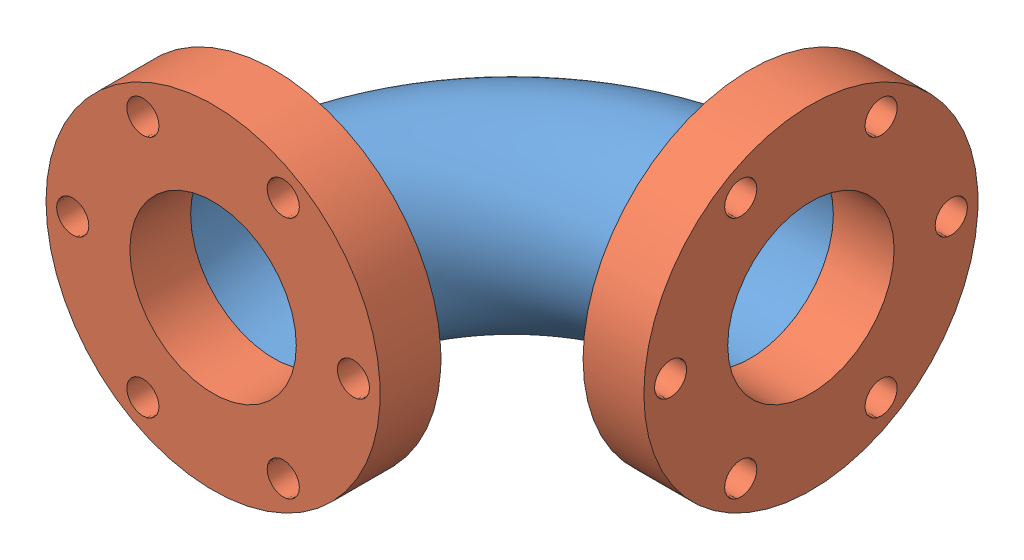
SolidWorks assembly 2.75in_elbow, configuration Default. Lengths in mm.
Overall size (97.41 69.85 97.41).
3 component instances, 2 part files, 3 mates.
Components (placement in the parent):
- 2.75in_elbow_tube-1: 2.75in_elbow_tube [Default] at (41.1147 -0.9291 41.2148) size (68.83 38.1 68.83)
- 2.75in_CF_flange-3: 2.75in_CF_flange [Default] at (-8.6693 -0.9291 53.9148) x (0 -1 0) z (1 0 0) size (69.85 12.7 69.85)
- 2.75in_CF_flange-4: 2.75in_CF_flange [Default] at (41.1147 -0.9291 -8.5692) x (0 1 0) z (0 0 -1) size (69.85 12.7 69.85)
Mates (geometry in assembly coordinates):
- Parallel2: parallel anti-aligned: line of 2.75in_CF_flange-4 through (41.1147 -0.9291 -8.5692) axis (0 0 1); line of assembly
- Coincident1: coincident anti-aligned: circle of 2.75in_elbow_tube-1; circle of 2.75in_CF_flange-3
- Coincident2: coincident anti-aligned: circle of 2.75in_elbow_tube-1; circle of 2.75in_CF_flange-4
